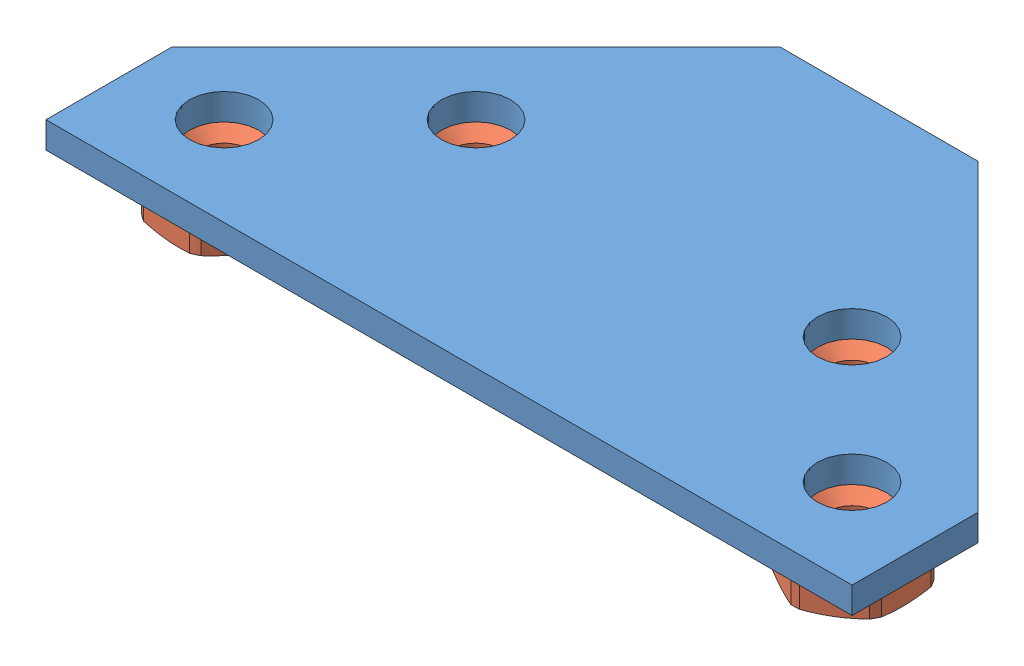
SolidWorks assembly ТП.017.01.06.00 - Средняя закладная, configuration 00. Lengths in mm.
Overall size (122.18 12.4 65.18).
5 component instances, 2 part files, 8 mates.
Components (placement in the parent):
- ТП.017.01.06.01 - Пластина средней закладной(Ст3)-1: ТП.017.01.06.01 - Пластина средней закладной(Ст3) [4мм] at origin size (122.18 4 65.18)
- Гайка (ГОСТ ISO 4032-2014)-1: Гайка (ГОСТ ISO 4032-2014) [Гайка М10 (ГОСТ ISO 4032)] at (-47.5919 -8.2 -13.5) x (0.908771 0 -0.417295) z (0 -1 0) size (16 17.77 8.4)
- Гайка (ГОСТ ISO 4032-2014)-2: Гайка (ГОСТ ISO 4032-2014) [Гайка М10 (ГОСТ ISO 4032)] at (-28.5 -8.2 -32.5919) x (0.813846 0 -0.58108) z (0 -1 0) size (16 17.77 8.4)
- Гайка (ГОСТ ISO 4032-2014)-3: Гайка (ГОСТ ISO 4032-2014) [Гайка М10 (ГОСТ ISO 4032)] at (28.5 -8.2 -32.5919) x (0.669446 0 -0.742861) z (0 -1 0) size (16 17.77 8.4)
- Гайка (ГОСТ ISO 4032-2014)-4: Гайка (ГОСТ ISO 4032-2014) [Гайка М10 (ГОСТ ISO 4032)] at (47.5919 -8.2 -13.5) x (0.47664 0 -0.879099) z (0 -1 0) size (16 17.77 8.4)
Mates (geometry in assembly coordinates):
- Совпадение1: coincident: plane of ТП.017.01.06.01 - Пластина средней закладной(Ст3)-1 through (0 -4 0) normal (0 -1 0); plane of Гайка (ГОСТ ISO 4032-2014)-1 through (-44.5456 -4 -6.866) normal (0 1 0)
- Концентричный1: concentric: cylinder of ТП.017.01.06.01 - Пластина средней закладной(Ст3)-1 through (-47.5919 -4 -13.5) axis (0 1 0) radius 5.25; cylinder of Гайка (ГОСТ ISO 4032-2014)-1 through (-47.5919 -160.9402 -13.5) axis (0 -1 0) radius 3.701
- Совпадение2: coincident: plane of ТП.017.01.06.01 - Пластина средней закладной(Ст3)-1 through (0 -4 0) normal (0 -1 0); plane of Гайка (ГОСТ ISO 4032-2014)-2 through (-24.2581 -4 -26.6508) normal (0 1 0)
- Концентричный2: concentric: cylinder of ТП.017.01.06.01 - Пластина средней закладной(Ст3)-1 through (-28.5 -4 -32.5919) axis (0 1 0) radius 5.25; cylinder of Гайка (ГОСТ ISO 4032-2014)-2 through (-28.5 -160.9402 -32.5919) axis (0 -1 0) radius 3.701
- Совпадение3: coincident: plane of ТП.017.01.06.01 - Пластина средней закладной(Ст3)-1 through (0 -4 0) normal (0 -1 0); plane of Гайка (ГОСТ ISO 4032-2014)-3 through (33.9229 -4 -27.7049) normal (0 1 0)
- Концентричный3: concentric: cylinder of ТП.017.01.06.01 - Пластина средней закладной(Ст3)-1 through (28.5 -4 -32.5919) axis (0 1 0) radius 5.25; cylinder of Гайка (ГОСТ ISO 4032-2014)-3 through (28.5 -160.9402 -32.5919) axis (0 -1 0) radius 3.701
- Совпадение4: coincident: plane of ТП.017.01.06.01 - Пластина средней закладной(Ст3)-1 through (0 -4 0) normal (0 -1 0); plane of Гайка (ГОСТ ISO 4032-2014)-4 through (54.0093 -4 -10.0205) normal (0 1 0)
- Концентричный4: concentric: cylinder of ТП.017.01.06.01 - Пластина средней закладной(Ст3)-1 through (47.5919 -4 -13.5) axis (0 1 0) radius 5.25; cylinder of Гайка (ГОСТ ISO 4032-2014)-4 through (47.5919 -160.9402 -13.5) axis (0 -1 0) radius 3.701
